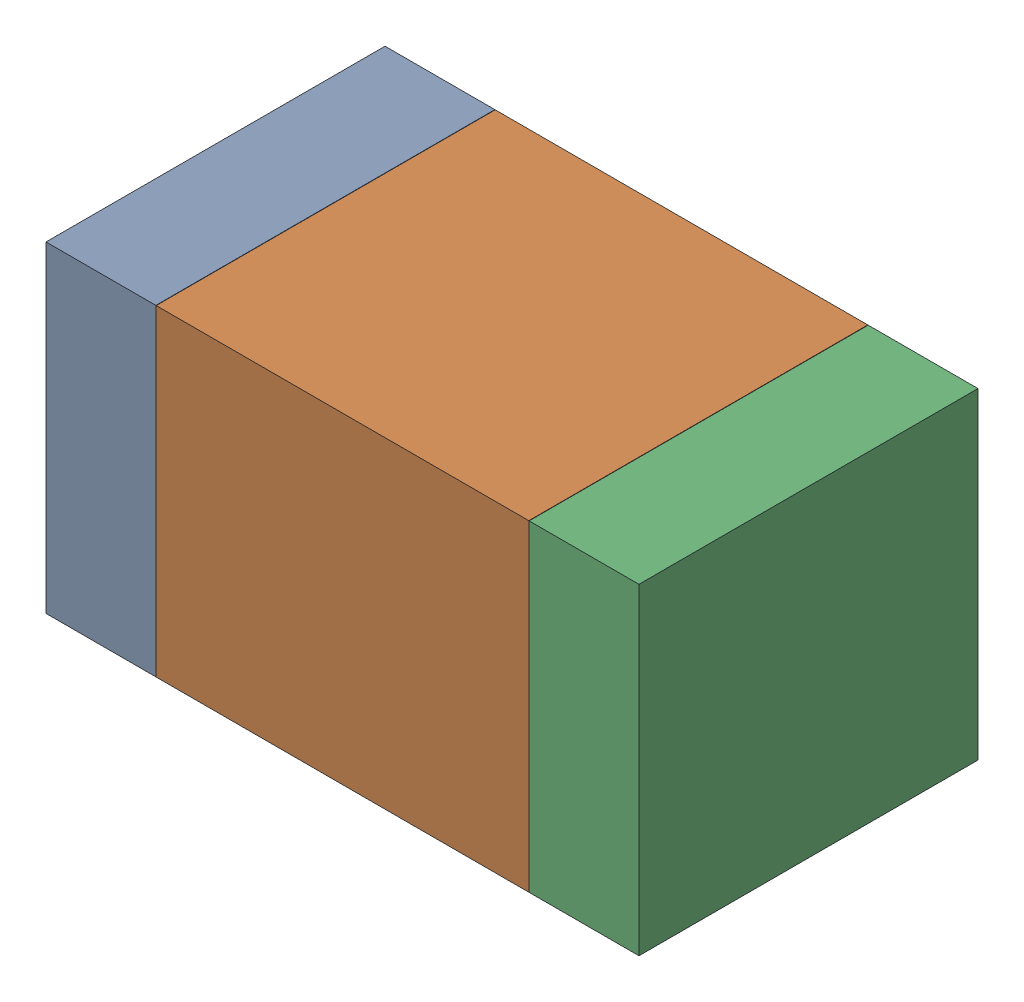
SolidWorks assembly R38, configuration Default. Lengths in mm.
Overall size (1.75 0.95 1).
6 component instances, 2 part files, 0 mates.
Components (placement in the parent):
- 6575498272-1: 6575498272 [Default] at (43.3565 19.558 0) size (0.32 0.95 1)
  - Extruded_8-1: Extruded_8 [Default] at origin size (0.32 0.95 1)
- 6575498112-1: 6575498112 [Default] at (44.069 19.558 0) size (1.1 0.95 1)
  - Extruded_9-1: Extruded_9 [Default] at origin size (1.1 0.95 1)
- 6575498272-2: 6575498272 [Default] at (44.7815 19.558 0) size (0.32 0.95 1)
  - Extruded_8-1: Extruded_8 [Default] at origin size (0.32 0.95 1)
